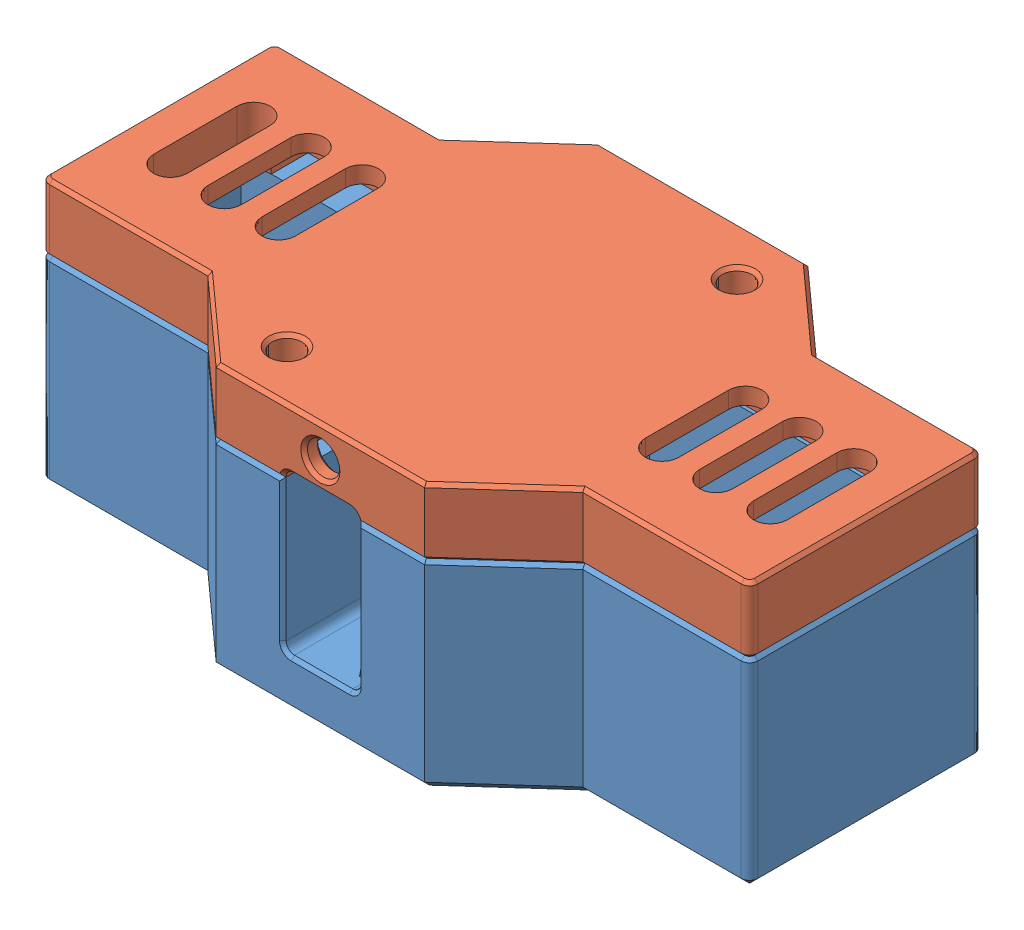
SolidWorks assembly load_sens_assem, configuration Default. Lengths in mm.
Overall size (85 32 46).
2 component instances, 2 part files, 2 mates.
Components (placement in the parent):
- load_sens_body_v3-1: load_sens_body_v3 [Default] at origin size (85 24 46)
- load_sens_lid-1: load_sens_lid [Default] at (0 25 0) x (1 0 0) z (0 0 -1) size (85 8 46)
Mates (geometry in assembly coordinates):
- Coincident2: coincident anti-aligned: circle of load_sens_body_v3-1; circle of load_sens_lid-1
- Coincident3: coincident anti-aligned: circle of load_sens_body_v3-1; circle of load_sens_lid-1
